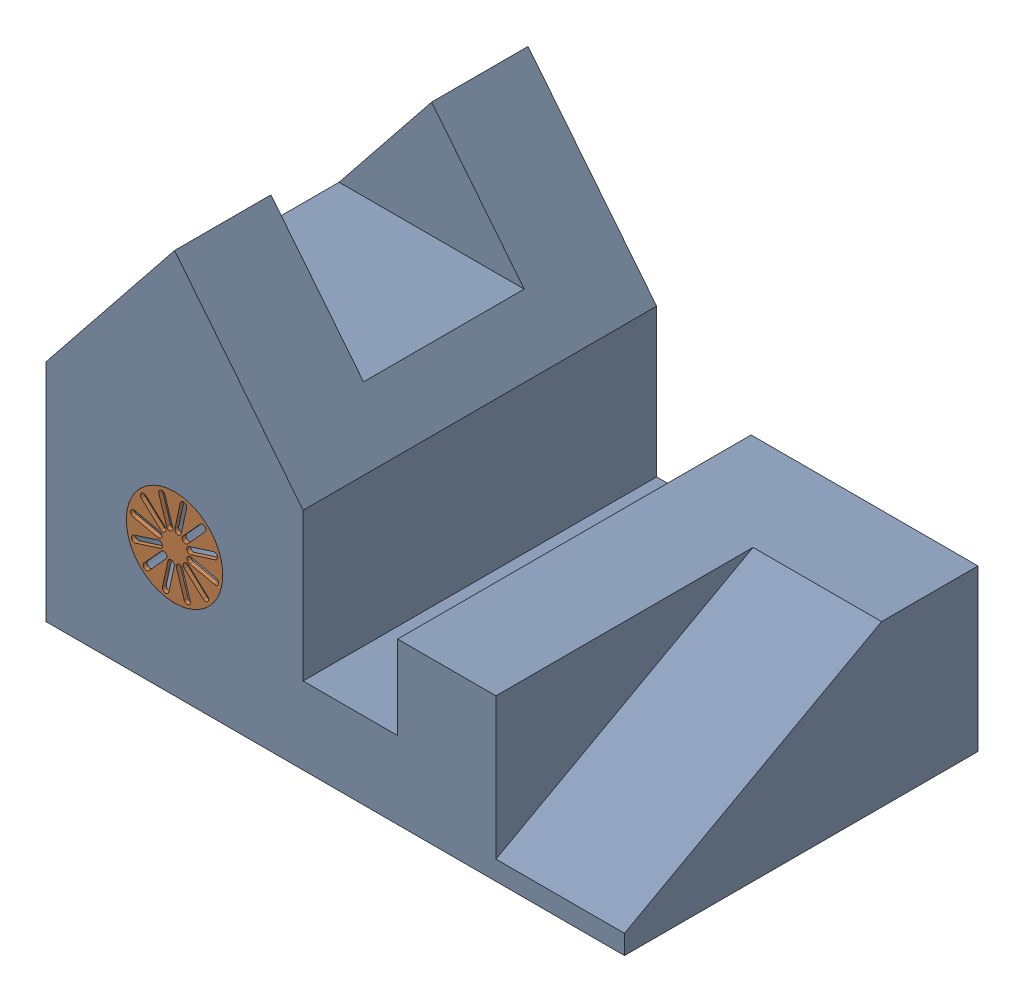
SolidWorks assembly Solidworks Class Activity 1, configuration Default. Lengths in mm.
Overall size (2286 1524 1397).
3 component instances, 2 part files, 7 mates.
Components (placement in the parent):
- Part2-1: Part2 [Default] at (1143 0 -698.5) size (2286 1524 1397)
- Part1-1: Part1 [Default] at (508 508 -11.43) x (0.213134 0.977023 0) z (0.977023 -0.213134 0) size (381 15.24 381)
- Part1-2: Part1 [Default] at (508 508 -1393.19) x (1 0 0) z (0 -1 0) size (381 15.24 381)
Mates (geometry in assembly coordinates):
- Coincident1: coincident aligned: plane of Part2-1 through (2286 1524 0) normal (0 0 1)
- Coincident2: coincident anti-aligned: plane of Part2-1 through (0 1524 0) normal (-1 0 0)
- Coincident3: coincident anti-aligned: plane of Part2-1 through (1143 0 -698.5) normal (0 -1 0)
- Concentric1: concentric anti-aligned: cylinder of Part2-1 through (508 508 -1397) axis (0 0 1) radius 190.5; cylinder of Part1-1 through (508 508 0) axis (0 0 -1) radius 190.5
- Coincident4: coincident aligned: circle of Part2-1; circle of Part1-1
- Concentric2: concentric anti-aligned: cylinder of Part2-1 through (508 508 -1397) axis (0 0 1) radius 190.5; cylinder of Part1-2 through (508 508 -1381.76) axis (0 0 -1) radius 190.5
- Coincident5: coincident aligned: circle of Part2-1; circle of Part1-2
